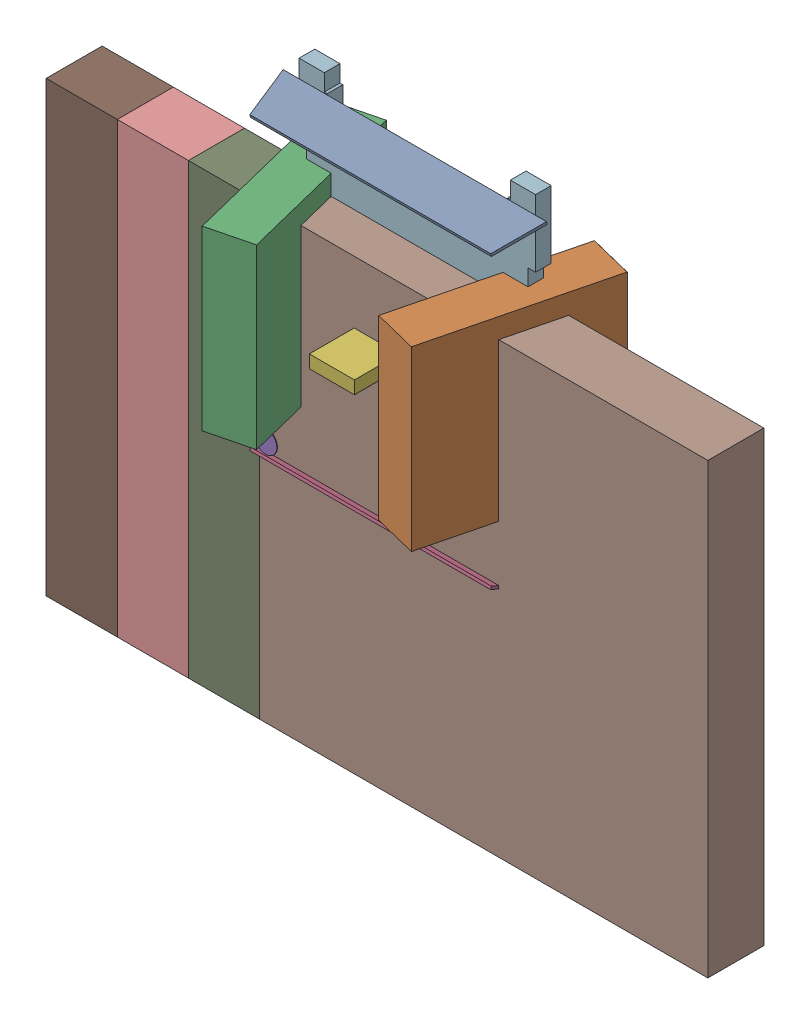
SolidWorks assembly Free-Models, configuration 默认. Lengths in mm.
Overall size (11.81 9.85 3.29).
24 component instances, 7 part files, 0 mates.
Components (placement in the parent):
- SIDE_S-1: SIDE_S [默认] at (1.9 5.4223 0.705) x (1 0 0) z (0 0.970296 0.241922) size (4.7 0.82 0.05)
  - Extruded-1: Extruded [默认] at origin size (4.7 0.82 0.05)
- SIDE_L-1: SIDE_L [默认] at (4.1508 2.775 0.705) x (0.241922 0 -0.970296) z (-0.970296 0 -0.241922) size (3.19 3.17 0.81)
  - Extruded_2-1: Extruded_2 [默认] at origin size (3.19 3.17 0.81)
- SIDE_L-1-1: SIDE_L-1 [默认] at (-0.3508 2.775 0.705) x (-0.241922 0 -0.970296) z (0.970296 0 -0.241922) size (3.19 3.17 0.81)
  - Extruded_2-1: Extruded_2 [默认] at origin size (3.19 3.17 0.81)
- SIDE_S-1-1: SIDE_S-1 [默认] at (1.9 0.1277 0.705) x (-1 0 0) z (0 -0.970296 0.241922) size (4.7 0.82 0.05)
  - Extruded-1: Extruded [默认] at origin size (4.7 0.82 0.05)
- 587257496-1: 587257496 [默认] at (0.0484 0.4796 1.12) size (0.4 0.4 0.01)
  - Cylinder-1: Cylinder [默认] at origin size (0.4 0.4 0.01)
- 750905040-1: 750905040 [默认] at (1.9 2.775 1) size (0.8 0.23 0.8)
  - Extruded_3-1: Extruded_3 [默认] at origin size (0.8 0.23 0.8)
- 266863104-1: 266863104 [默认] at (1.9025 2.775 0.02) size (0.8 1.14 0.8)
  - Extruded_4-1: Extruded_4 [默认] at origin size (0.8 1.14 0.8)
- 500156144-1: 500156144 [默认] at (3.81 0 0) size (8 8 1)
  - Extruded_5-1: Extruded_5 [默认] at origin size (8 8 1)
- 500156144-1-1: 500156144-1 [默认] at (2.54 0 0) size (8 8 1)
  - Extruded_5-1: Extruded_5 [默认] at origin size (8 8 1)
- 500156144-2-1: 500156144-2 [默认] at (1.27 0 0) size (8 8 1)
  - Extruded_5-1: Extruded_5 [默认] at origin size (8 8 1)
- 500156144-3-1: 500156144-3 [默认] at origin size (8 8 1)
  - Extruded_5-1: Extruded_5 [默认] at origin size (8 8 1)
- 500160368-1: 500160368 [默认] at (1.905 3.335 0) size (5.15 5.03 0.28)
  - Extruded_6-1: Extruded_6 [默认] at origin size (5.15 5.03 0.28)
